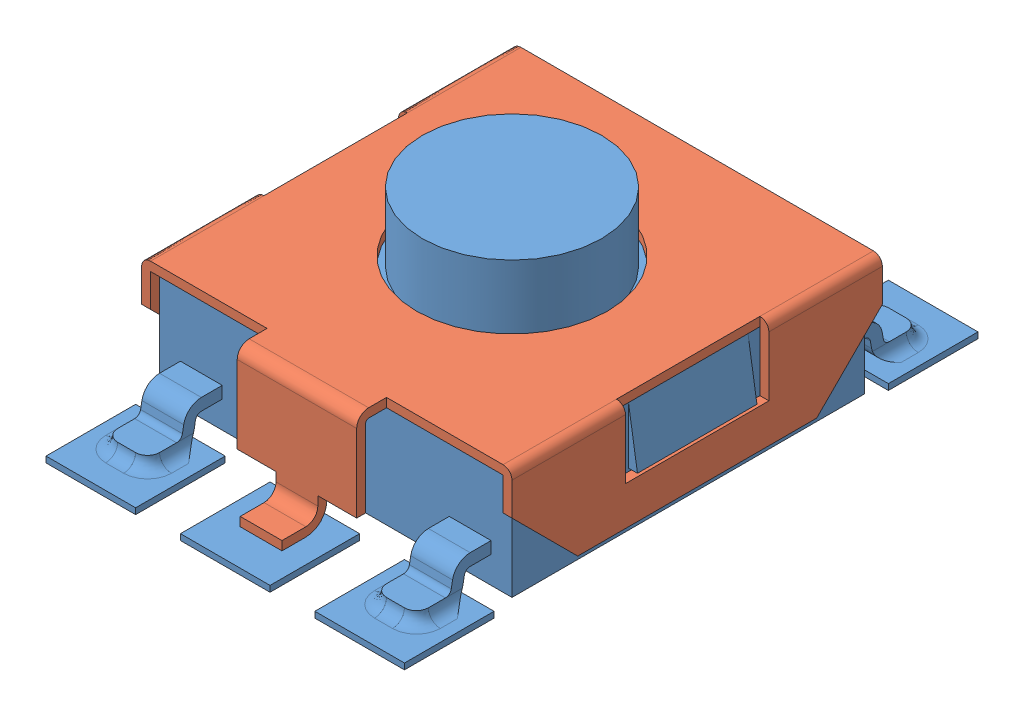
SolidWorks assembly RESET Montaj, configuration Default. Lengths in mm.
Overall size (6.2 3.1 9.6).
2 component instances, 2 part files, 6 mates.
Components (placement in the parent):
- RESET CORE-1: RESET CORE [Default] at (0 0.1 0) x (-1 0 0) z (0 0 -1) size (6.2 3.1 9.6)
- RESET-1: RESET [Default] at (0 0.1 0) x (0 0 1) z (-1 0 0) size (7.3 2 6.2)
Mates (geometry in assembly coordinates):
- Coincident4: coincident anti-aligned: plane of RESET CORE-1 through (0 0.1 0) normal (0 0 -1); plane of assembly through (0 0 0) normal (0 0 1)
- Coincident5: coincident anti-aligned: plane of RESET CORE-1 through (0 0.1 0) normal (-1 0 0); plane of assembly through (0 0 0) normal (1 0 0)
- Coincident6: coincident anti-aligned: plane of RESET CORE-1 through (0 0 0) normal (0 -1 0); plane of assembly through (0 0 0) normal (0 1 0)
- Coincident7: coincident: plane of RESET-1 through (0 0.1 0) normal (0 0 1); plane of assembly through (0 0 0) normal (0 0 1)
- Coincident9: coincident anti-aligned: plane of RESET-1 through (0 0.1 0) normal (-1 0 0); plane of assembly
- Coincident10: coincident aligned: plane of RESET CORE-1; plane of RESET-1
